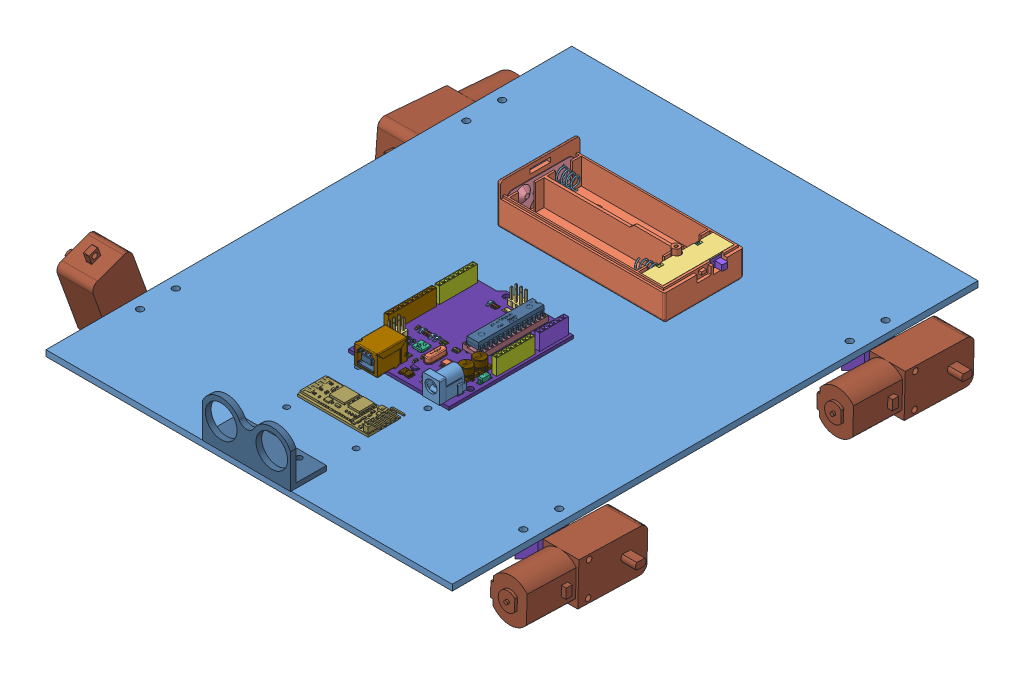
SolidWorks assembly rover assembly, configuration Default. Lengths in mm.
Overall size (269.24 73.48 279.75).
111 component instances, 49 part files, 21 mates.
Components (placement in the parent):
- rover base-1: rover base [Default] at (-115.0005 22.7638 132.7863) size (215.9 3.17 279.4)
- 3.7V 2X 18650 BATTERY HOLDER WITH ON OFF SWITCH (1)-1: 3.7V 2X 18650 BATTERY HOLDER WITH ON OFF SWITCH (1) [Default] at (-7.1479 25.9388 -64.5235) size (90.2 22 42.01)
  - 3.7V 2X 18650 BATTERY HOLDER WITH ON OFF SWITCH (1).STEP-1: 3.7V 2X 18650 BATTERY HOLDER WITH ON OFF SWITCH (1).STEP [Default] at origin size (90.8 22 42.01)
    - CASE, 3.7V 2X 18650 BATTERY HOLDER WITH ON OFF SWITCH.STEP-1: CASE, 3.7V 2X 18650 BATTERY HOLDER WITH ON OFF SWITCH.STEP [Default] at origin size (89 22 42.01)
    - SWITCH AND WIRING COVER, 3.7V 2X 18650 BATTERY HOLDER WITH ON OFF SWITCH.STEP-1: SWITCH AND WIRING COVER, 3.7V 2X 18650 BATTERY HOLDER WITH ON OFF SWITCH.STEP [Default] at (35.95 15 0) x (1 0 0) z (0 0 -1) size (11.3 3.7 38)
    - BATTERY CONDUCTION CLIP, 3.7V 2X 18650 BATTERY HOLDER WITH ON OFF SWITCH.STEP-1: BATTERY CONDUCTION CLIP, 3.7V 2X 18650 BATTERY HOLDER WITH ON OFF SWITCH.STEP [Default] at (-42.5 8.2 0) x (0 0 1) z (0 1 0) size (37 2.6 14)
    - SPRING, 3.7V 2X 18650 BATTERY HOLDER WITH ON OFF SWITCH.STEP-1: SPRING, 3.7V 2X 18650 BATTERY HOLDER WITH ON OFF SWITCH.STEP [Default] at (-37.0934 10.6 -9.5) x (0 0 -1) z (0 -1 0) size (7.33 10.2 7.44)
    - BATTERY CONDUCTION CLIP, POSITIVE TERMINAL, 3.7V 2X 18650 BATTERY HOLDER WITH ON OFF SWITCH.STEP-1: BATTERY CONDUCTION CLIP, POSITIVE TERMINAL, 3.7V 2X 18650 BATTERY HOLDER WITH ON OFF SWITCH.STEP [Default] at (30.1 7.7 -9.75) x (0 0 -1) z (0 1 0) size (15 6.6 13)
    - BATTERY CONDUCTION CLIP, NEGATIVE TERMINAL, 3.7V 2X 18650 BATTERY HOLDER WITH ON OFF SWITCH.STEP-1: BATTERY CONDUCTION CLIP, NEGATIVE TERMINAL, 3.7V 2X 18650 BATTERY HOLDER WITH ON OFF SWITCH.STEP [Default] at (30.1 7.7 9.75) x (0 0 -1) z (0 1 0) size (15 5.6 13)
    - SPRING, 3.7V 2X 18650 BATTERY HOLDER WITH ON OFF SWITCH.STEP-2: SPRING, 3.7V 2X 18650 BATTERY HOLDER WITH ON OFF SWITCH.STEP [Default] at (24.6934 9.6 9.75) x (0 0 -1) z (0 1 0) size (7.33 10.2 7.44)
    - SLIDE SWITCH SPDT, 3.7V 2X 18650 BATTERY HOLDER WITH ON OFF SWITCH_OFF.STEP-1: SLIDE SWITCH SPDT, 3.7V 2X 18650 BATTERY HOLDER WITH ON OFF SWITCH_OFF.STEP [Default] at (36.7 11.3 -8.7) x (0 0 -1) z (0 -1 0) size (19 12 6)
    - COVER, 3.7V 2X 18650 BATTERY HOLDER WITH ON OFF SWITCH.STEP-1: COVER, 3.7V 2X 18650 BATTERY HOLDER WITH ON OFF SWITCH.STEP [Default] at (1 22 0) x (1 0 0) z (0 0 -1) size (89.6 11.9 42) (hidden)
- arduino uno.STEP-1: arduino uno.STEP [Default] at (20.046 27.5888 53.6475) size (53.34 15.26 74.94)
  - USB type b.STEP-1: USB type b.STEP [Default] at (-38.02 0.43 6.35) size (13.91 15.21 16.51)
    - USB SHELL.STEP-1: USB SHELL.STEP [Default] at origin size (13.91 15.21 16.51)
    - USB core.STEP-1: USB core.STEP [Default] at origin size (11.3 10.68 15.75)
    - usb top contact.STEP-1: usb top contact.STEP [Default] at (1.25 6.09 -0.38) size (1 9.67 13.76)
    - usb btm contact.STEP-1: usb btm contact.STEP [Default] at (1.25 4.41 -0.38) size (1 6.84 11.76)
    - usb btm contact.STEP-2: usb btm contact.STEP [Default] at (-1.25 4.41 -0.38) size (1 6.84 11.76)
    - usb top contact.STEP-2: usb top contact.STEP [Default] at (-1.25 6.09 -0.38) size (1 9.67 13.76)
  - dip28.STEP-1: dip28.STEP [Default] at (-16.383 1.5 -46.355) x (0 0 -1) z (1 0 0) size (35.48 7.37 10.1)
    - dip28-0.STEP-1: dip28-0.STEP [Default] at origin size (35.48 2.8 10.1)
    - dip socket pin.STEP-1: dip socket pin.STEP [Default] at (16.51 2.8 -3.81) size (1.7 7.37 1.7)
    - dip socket pin.STEP-2: dip socket pin.STEP [Default] at (16.51 2.8 3.81) size (1.7 7.37 1.7)
    - dip socket pin.STEP-3: dip socket pin.STEP [Default] at (13.97 2.8 -3.81) size (1.7 7.37 1.7)
    - dip socket pin.STEP-4: dip socket pin.STEP [Default] at (13.97 2.8 3.81) size (1.7 7.37 1.7)
    - dip socket pin.STEP-5: dip socket pin.STEP [Default] at (11.43 2.8 -3.81) size (1.7 7.37 1.7)
    - dip socket pin.STEP-6: dip socket pin.STEP [Default] at (11.43 2.8 3.81) size (1.7 7.37 1.7)
    - dip socket pin.STEP-7: dip socket pin.STEP [Default] at (8.89 2.8 -3.81) size (1.7 7.37 1.7)
    - dip socket pin.STEP-8: dip socket pin.STEP [Default] at (8.89 2.8 3.81) size (1.7 7.37 1.7)
    - dip socket pin.STEP-9: dip socket pin.STEP [Default] at (6.35 2.8 -3.81) size (1.7 7.37 1.7)
    - dip socket pin.STEP-10: dip socket pin.STEP [Default] at (6.35 2.8 3.81) size (1.7 7.37 1.7)
    - dip socket pin.STEP-11: dip socket pin.STEP [Default] at (3.81 2.8 -3.81) size (1.7 7.37 1.7)
    - dip socket pin.STEP-12: dip socket pin.STEP [Default] at (3.81 2.8 3.81) size (1.7 7.37 1.7)
    - dip socket pin.STEP-13: dip socket pin.STEP [Default] at (1.27 2.8 -3.81) size (1.7 7.37 1.7)
    - dip socket pin.STEP-14: dip socket pin.STEP [Default] at (1.27 2.8 3.81) size (1.7 7.37 1.7)
    - dip socket pin.STEP-15: dip socket pin.STEP [Default] at (-1.27 2.8 -3.81) size (1.7 7.37 1.7)
    - dip socket pin.STEP-16: dip socket pin.STEP [Default] at (-1.27 2.8 3.81) size (1.7 7.37 1.7)
    - dip socket pin.STEP-17: dip socket pin.STEP [Default] at (-3.81 2.8 -3.81) size (1.7 7.37 1.7)
    - dip socket pin.STEP-18: dip socket pin.STEP [Default] at (-3.81 2.8 3.81) size (1.7 7.37 1.7)
    - dip socket pin.STEP-19: dip socket pin.STEP [Default] at (-6.35 2.8 -3.81) size (1.7 7.37 1.7)
    - dip socket pin.STEP-20: dip socket pin.STEP [Default] at (-6.35 2.8 3.81) size (1.7 7.37 1.7)
    - dip socket pin.STEP-21: dip socket pin.STEP [Default] at (-8.89 2.8 -3.81) size (1.7 7.37 1.7)
    - dip socket pin.STEP-22: dip socket pin.STEP [Default] at (-8.89 2.8 3.81) size (1.7 7.37 1.7)
    - dip socket pin.STEP-23: dip socket pin.STEP [Default] at (-11.43 2.8 -3.81) size (1.7 7.37 1.7)
    - dip socket pin.STEP-24: dip socket pin.STEP [Default] at (-11.43 2.8 3.81) size (1.7 7.37 1.7)
    - dip socket pin.STEP-25: dip socket pin.STEP [Default] at (-13.97 2.8 -3.81) size (1.7 7.37 1.7)
    - dip socket pin.STEP-26: dip socket pin.STEP [Default] at (-13.97 2.8 3.81) size (1.7 7.37 1.7)
    - dip socket pin.STEP-27: dip socket pin.STEP [Default] at (-16.51 2.8 -3.81) size (1.7 7.37 1.7)
    - dip socket pin.STEP-28: dip socket pin.STEP [Default] at (-16.51 2.8 3.81) size (1.7 7.37 1.7)
  - RESET BUTTON.STEP-1: RESET BUTTON.STEP [Default] at (-49.403 0 -6.35) size (6.2 3.1 9.6)
    - RESET CORE.STEP-1: RESET CORE.STEP [Default] at (0 0.1 0) x (-1 0 0) z (0 0 -1) size (6.2 3.1 9.6)
    - RESET.STEP-1: RESET.STEP [Default] at (0 0.1 0) x (0 0 1) z (-1 0 0) size (7.3 2 6.2)
  - unoboard blue.STEP-1: unoboard blue.STEP [Default] at origin size (53.34 1.65 68.58)
  - 47uf CAP Dcase.STEP-1: 47uf CAP Dcase.STEP [Default] at (-9.4141 0 -18.4991) x (0 0 -1) z (1 0 0) size (6.6 5.81 8)
  - power jack.STEP-1: power jack.STEP [Default] at (-7.675 0 1.905) size (11.2 15.2 15.9)
  - 47uf CAP Dcase.STEP-2: 47uf CAP Dcase.STEP [Default] at (-9.4141 0 -25.7132) x (0 0 -1) z (1 0 0) size (6.6 5.81 8)
  - crystal.STEP-1: crystal.STEP [Default] at (-26.162 0 -18.923) x (1 0 0) z (0 0 -1) size (4 5 11)
  - 2pin_header__02.STEP-1: 2pin_header__02.STEP [Default] at (-46.23 0 -15.75) size (5 11.75 2.54)
  - nano - reg.STEP-1: nano - reg.STEP [Default] at (-17.399 0 -7.747) size (6.5 1.69 8.3)
  - led.STEP-1: led.STEP [Default] at (-34.29 0 -27.94) x (0 0 1) z (-1 0 0) size (4 0.85 1.47)
  - 2pin_header__02.STEP-2: 2pin_header__02.STEP [Default] at (-30.43 0 -64.91) x (0 0 1) z (-1 0 0) size (5 11.75 2.54)
  - 2pin_header__02.STEP-3: 2pin_header__02.STEP [Default] at (-27.89 0 -64.91) x (0 0 1) z (-1 0 0) size (5 11.75 2.54)
  - 2pin_header__02.STEP-4: 2pin_header__02.STEP [Default] at (-25.35 0 -64.91) x (0 0 1) z (-1 0 0) size (5 11.75 2.54)
  - 2pin_header__02.STEP-5: 2pin_header__02.STEP [Default] at (-46.23 0 -18.29) size (5 11.75 2.54)
  - 2pin_header__02.STEP-6: 2pin_header__02.STEP [Default] at (-46.23 0 -20.83) size (5 11.75 2.54)
  - atmega16u2.STEP-1: atmega16u2.STEP [Default] at (-34.671 0.06 -20) x (1 0 0) z (0 0 -1) size (5.5 1.01 5.5)
  - led.STEP-2: led.STEP [Default] at (-36.83 0 -27.94) x (0 0 1) z (-1 0 0) size (4 0.85 1.47)
  - led.STEP-3: led.STEP [Default] at (-42.037 0 -27.94) x (0 0 1) z (-1 0 0) size (4 0.85 1.47)
  - led.STEP-4: led.STEP [Default] at (-36.576 0 -58.42) x (0 0 1) z (-1 0 0) size (4 0.85 1.47)
  - 8 PORT HEADER.STEP-1: 8 PORT HEADER.STEP [Default] at (-50.8 0 -45.72) x (0 0 -1) z (1 0 0) size (20.32 10.51 2.41)
  - 8 PORT HEADER.STEP-2: 8 PORT HEADER.STEP [Default] at (-2.54 0 -27.94) x (0 0 -1) z (1 0 0) size (20.32 10.51 2.41)
  - 6 PORT HEADER.STEP-1: 6 PORT HEADER.STEP [Default] at (-2.54 0 -50.8) x (0 0 -1) z (1 0 0) size (15.24 10.51 2.41)
  - 10 PORT HEADER.STEP-1: 10 PORT HEADER.STEP [Default] at (-50.8 0 -18.796) x (0 0 -1) z (1 0 0) size (25.4 10.51 2.41)
  - ATMEL328P.STEP-1: ATMEL328P.STEP [Default] at (-16.383 4.3 -46.355) x (0 0 -1) z (1 0 0) size (35 7.27 7.87)
  - 102 RESISTOR PACK.STEP-1: 102 RESISTOR PACK.STEP [Default] at (-33.782 0 -58.42) size (3.2 0.46 3)
  - 102 RESISTOR PACK.STEP-2: 102 RESISTOR PACK.STEP [Default] at (-39.37 0 -27.94) size (3.2 0.46 3)
  - 103 RESISTOR PACK.STEP-1: 103 RESISTOR PACK.STEP [Default] at (-23.876 0 -27.94) size (3.2 0.46 3)
  - 220 RESISTOR PACK.STEP-1: 220 RESISTOR PACK.STEP [Default] at (-36.83 0 -12.827) size (3.2 0.46 3)
  - 16mhz crystal - measured.STEP-1: 16mhz crystal - measured.STEP [Default] at (-24.892 0 -41.275) x (0 0 -1) z (1 0 0) size (3.4 0.8 2)
  - PADS001.STEP-1: PADS001.STEP [Default] at (-39.878 0.1 -18.288) x (-1 0 0) z (0 0 1) size (4.54 0.1 4.54)
  - 603 cap on pad.STEP-1: 603 cap on pad.STEP [Default] at (-44.45 0 -27.94) x (0 0 -1) z (1 0 0) size (2.76 0.9 1.03)
  - ssot3.STEP-1: ssot3.STEP [Default] at (-26.5 0 -8.128) x (-1 0 0) z (0 0 -1) size (3 1.13 3.09)
  - mf-msmf050-2.STEP-1: mf-msmf050-2.STEP [Default] at (-26.5 0 -4.064) size (5.86 1.02 3.72)
  - 603 cap on pad.STEP-2: 603 cap on pad.STEP [Default] at (-29.845 0 -27.94) x (0 0 -1) z (1 0 0) size (2.76 0.9 1.03)
  - 603 cap on pad.STEP-3: 603 cap on pad.STEP [Default] at (-31.496 0 -27.94) x (0 0 -1) z (1 0 0) size (2.76 0.9 1.03)
  - lmv358.STEP-1: lmv358.STEP [Default] at (-15.24 0 -21.971) x (0 0 -1) z (1 0 0) size (3.7 1.4 2.9)
  - 603 cap on pad.STEP-4: 603 cap on pad.STEP [Default] at (-15.24 0 -18.415) size (2.76 0.9 1.03)
  - 603 cap on pad.STEP-5: 603 cap on pad.STEP [Default] at (-29.845 0 -12.065) x (0 0 1) z (-1 0 0) size (2.76 0.9 1.03)
  - 603 cap on pad.STEP-6: 603 cap on pad.STEP [Default] at (-29.591 0 -22.352) x (0 0 1) z (-1 0 0) size (2.76 0.9 1.03)
  - 603 cap on pad.STEP-7: 603 cap on pad.STEP [Default] at (-29.591 0 -16.002) x (0 0 1) z (-1 0 0) size (2.76 0.9 1.03)
  - 603 cap on pad.STEP-8: 603 cap on pad.STEP [Default] at (-41.91 0 -12.7) x (0 0 1) z (-1 0 0) size (2.76 0.9 1.03)
  - lp2985dgkr.STEP-1: lp2985dgkr.STEP [Default] at (-20.32 0 -19.05) x (0 0 -1) z (1 0 0) size (5.85 1.1 3)
  - cd1206 diode.STEP-1: cd1206 diode.STEP [Default] at (-27.94 0 -59.436) x (0 0 -1) z (1 0 0) size (2.01 0.96 5)
  - cd1206 diode.STEP-2: cd1206 diode.STEP [Default] at (-46.228 0 -13.081) x (0 0 1) z (-1 0 0) size (2.01 0.96 5)
  - 603 resistor.STEP-1: 603 resistor.STEP [Default] at (-29.591 0 -19.05) x (0 0 1) z (-1 0 0) size (2.36 0.61 1.02)
  - blm21.STEP-1: blm21.STEP [Default] at (-45.085 0 -7.62) x (0 0 -1) z (1 0 0) size (2.78 0.95 1.32)
  - m7 diode.STEP-1: m7 diode.STEP [Default] at (-2.794 0 -21.59) x (0 0 -1) z (1 0 0) size (6.66 2.35 2.5)
  - MLC0603.STEP-1: MLC0603.STEP [Default] at (-33.655 0 -12.827) x (0 0 -1) z (1 0 0) size (2.36 0.6 1.02)
  - MLC0603.STEP-2: MLC0603.STEP [Default] at (-39.37 0 -12.827) x (0 0 -1) z (1 0 0) size (2.36 0.6 1.02)
- MotorMountv2-2: MotorMountv2 [Default] at (100.8995 22.7638 72.7783) x (0 0 -1) z (0 1 0) size (28.45 11.05 22.83)
- L298N Motor Driver-1: L298N Motor Driver [Default] at (-5.5989 22.7638 76.769) x (0.014938 0 -0.999888) z (-0.999888 0 -0.014938) size (43.5 26 43.5)
- UltrasonicHolder-1: UltrasonicHolder [Default] at (15.2086 27.7878 146.62) x (0.005213 0 -0.999986) z (0 1 0) size (19.05 47 24.74)
- GearBox-1: GearBox [Default] at (110.4245 -0.3403 66.8101) x (1 0 0) z (0 0.028426 0.999596) size (29.21 22.48 70.02)
- hc05-1: hc05 [Varsayılan] at (-26.6228 25.9388 87.4976) x (1 0 0) z (0 1 0) size (42.6 16.1 5.9)
- GearBox-2: GearBox [Default] at (110.4245 -0.3403 -106.6365) x (1 0 0) z (0 0.028426 0.999596) size (29.21 22.48 70.02)
- MotorMountv2-3: MotorMountv2 [Default] at (100.8995 22.7638 -100.6684) x (0 0 -1) z (0 1 0) size (28.45 11.05 22.83)
- GearBox-3: GearBox [Default] at (-124.5255 1.1312 -79.2777) x (-1 0 0) z (0 -0.081237 -0.996695) size (29.21 22.48 70.02)
- MotorMountv2-4: MotorMountv2 [Default] at (-115.0005 22.7638 -87.3964) x (0 0 1) z (0 1 0) size (28.45 11.05 22.83)
- GearBox-4: GearBox [Default] at (-124.5255 25.289 102.7696) x (-1 0 0) z (0 -0.940134 -0.340805) size (29.21 22.48 70.02)
- MotorMountv2-5: MotorMountv2 [Default] at (-115.0005 22.7638 85.9692) x (0 0 1) z (0 1 0) size (28.45 11.05 22.83)
Mates (geometry in assembly coordinates):
- Coincident1: coincident anti-aligned: plane of rover base-1 through (-115.0005 25.9388 132.7863) normal (0 1 0); plane of 3.7V 2X 18650 BATTERY HOLDER WITH ON OFF SWITCH (1)-1/3.7V 2X 18650 BATTERY HOLDER WITH ON OFF SWITCH (1).STEP-1/CASE, 3.7V 2X 18650 BATTERY HOLDER WITH ON OFF SWITCH.STEP-1 through (-7.1479 25.9388 -64.5235) normal (0 -1 0)
- Coincident2: coincident anti-aligned: plane of rover base-1 through (-115.0005 25.9388 132.7863) normal (0 1 0); plane of arduino uno.STEP-1/unoboard blue.STEP-1 through (20.046 25.9388 53.6475) normal (0 -1 0)
- Coincident5: coincident anti-aligned: plane of rover base-1 through (-115.0005 25.9388 132.7863) normal (0 1 0); plane of UltrasonicHolder-1 through (15.3782 25.9388 114.0865) normal (0 -1 0)
- Coincident7: coincident anti-aligned: plane of rover base-1 through (-115.0005 22.7638 132.7863) normal (0 -1 0); plane of L298N Motor Driver-1 through (-5.5989 22.7638 76.769) normal (0 1 0)
- Coincident8: coincident anti-aligned: plane of rover base-1 through (-115.0005 25.9388 132.7863) normal (0 1 0); plane of hc05-1 through (-26.6228 25.9388 87.4976) normal (0 -1 0)
- Coincident10: coincident anti-aligned: plane of MotorMountv2-2 through (100.8995 22.7638 72.7783) normal (1 0 0); plane of GearBox-1 through (100.8995 22.5751 84.5174) normal (-1 0 0)
- Concentric1: concentric anti-aligned: circle of MotorMountv2-2; circle of GearBox-1
- Coincident12: coincident anti-aligned: plane of rover base-1 through (-115.0005 22.7638 132.7863) normal (0 -1 0); plane of MotorMountv2-2 through (94.5495 22.7638 72.7783) normal (0 1 0)
- Coincident13: coincident aligned: line of rover base-1 through (100.8995 22.7638 132.7863) axis (0 0 -1); line of MotorMountv2-2 through (100.8995 22.7638 87.2743) axis (0 0 -1)
- Concentric8: concentric anti-aligned: circle of GearBox-2; circle of MotorMountv2-3
- Coincident14: coincident anti-aligned: plane of GearBox-2 through (100.8995 22.5751 -88.9293) normal (-1 0 0); plane of MotorMountv2-3 through (100.8995 22.7638 -100.6684) normal (1 0 0)
- Coincident15: coincident anti-aligned: plane of rover base-1 through (-115.0005 22.7638 132.7863) normal (0 -1 0); plane of MotorMountv2-3 through (94.5495 22.7638 -100.6684) normal (0 1 0)
- Coincident16: coincident aligned: line of rover base-1 through (100.8995 22.7638 132.7863) axis (0 0 -1); line of MotorMountv2-3 through (100.8995 22.7638 -86.1723) axis (0 0 -1)
- Coincident17: coincident anti-aligned: plane of GearBox-3 through (-115.0005 21.9692 -99.3885) normal (1 0 0); plane of MotorMountv2-4 through (-115.0005 22.7638 -87.3964) normal (-1 0 0)
- Concentric9: concentric anti-aligned: circle of GearBox-3; circle of MotorMountv2-4
- Coincident18: coincident anti-aligned: plane of rover base-1 through (-115.0005 22.7638 132.7863) normal (0 -1 0); plane of MotorMountv2-4 through (-108.6505 22.7638 -87.3964) normal (0 1 0)
- Coincident21: coincident aligned: line of rover base-1 through (-115.0005 22.7638 -146.6137) axis (0 0 1); line of MotorMountv2-4 through (-115.0005 22.7638 -101.8924) axis (0 0 1)
- Coincident22: coincident anti-aligned: plane of GearBox-4 through (-115.0005 15.6711 75.4537) normal (1 0 0); plane of MotorMountv2-5 through (-115.0005 22.7638 85.9692) normal (-1 0 0)
- Concentric10: concentric anti-aligned: circle of GearBox-4; circle of MotorMountv2-5
- Coincident23: coincident anti-aligned: plane of rover base-1 through (-115.0005 22.7638 132.7863) normal (0 -1 0); plane of MotorMountv2-5 through (-108.6505 22.7638 85.9692) normal (0 1 0)
- Coincident24: coincident: plane of rover base-1 through (-115.0005 25.9388 -146.6137) normal (-1 0 0); line of MotorMountv2-5 through (-115.0005 22.7638 71.4731) axis (0 0 1)
